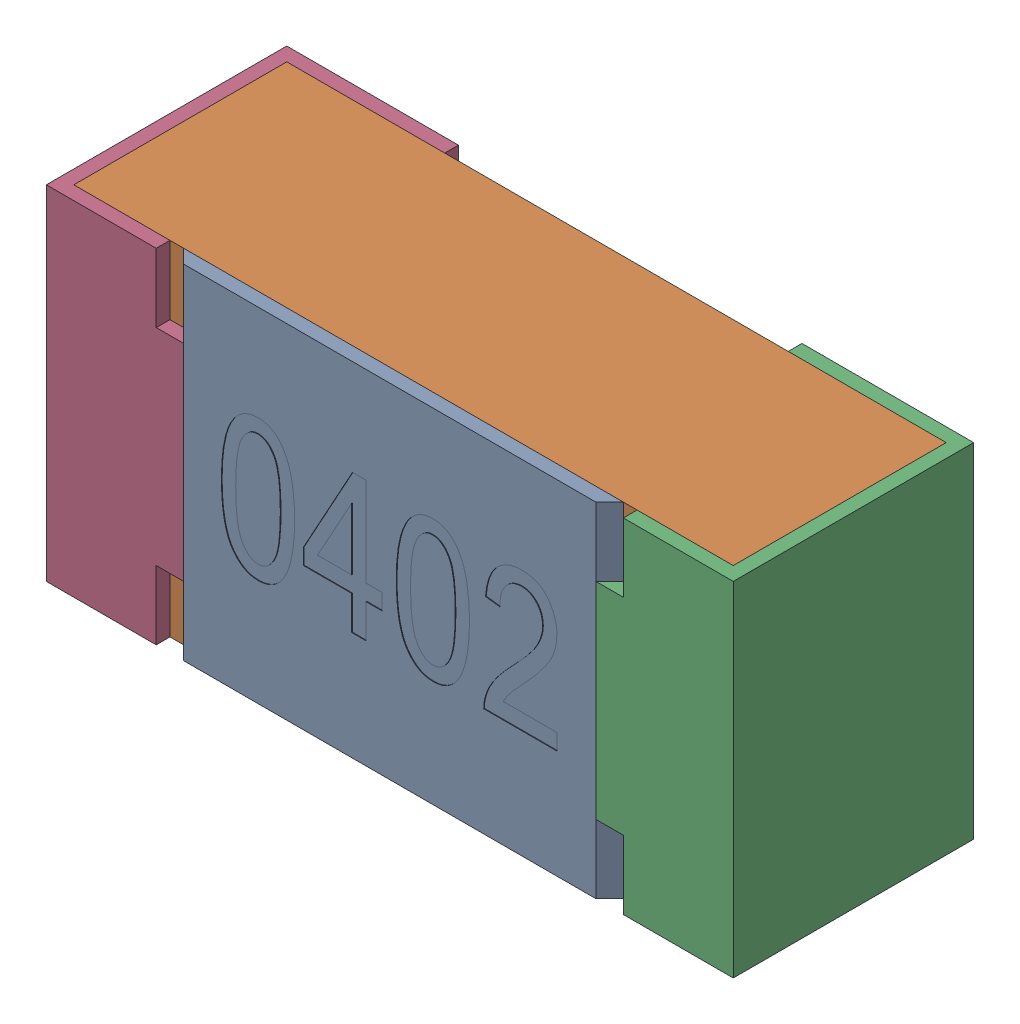
SolidWorks assembly R5, configuration Standard. Lengths in mm.
Overall size (1 0.5 0.35).
5 component instances, 4 part files, 0 mates.
Components (placement in the parent):
- R5-subassembly-1-1: R5-subassembly-1 [Standard] at (4.4001 -21 0) x (1 0 0) z (0 0 1) size (1 0.5 0.35)
  - User Library-R_0402-1: User Library-R_0402 [Standard] at origin size (0.64 0.5 0.02)
  - User Library-R_0402-1-1: User Library-R_0402-1 [Standard] at origin size (0.96 0.5 0.31)
  - User Library-R_0402-2-1: User Library-R_0402-2 [Standard] at origin size (0.25 0.5 0.35)
  - User Library-R_0402-3-1: User Library-R_0402-3 [Standard] at origin size (0.25 0.5 0.35)
